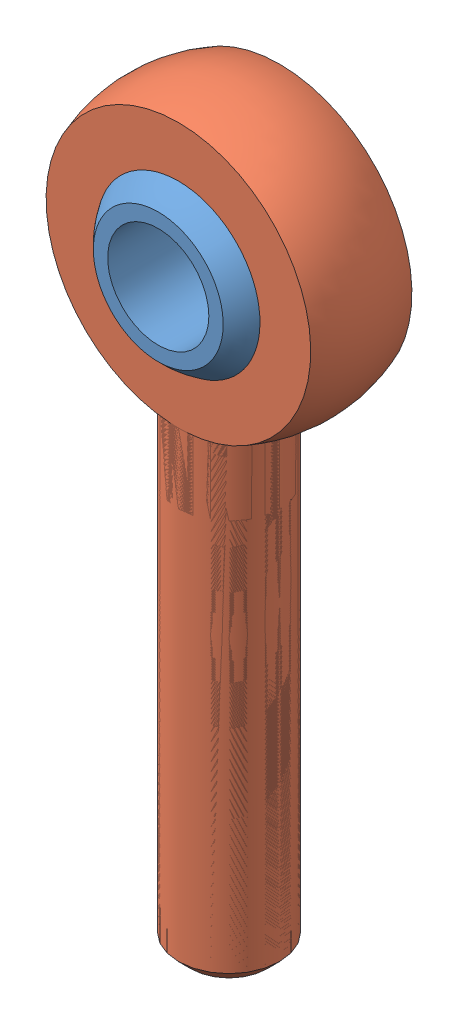
SolidWorks assembly RodEnd312Male, configuration Default. Lengths in mm.
Overall size (22.23 58.75 22.2).
2 component instances, 2 part files, 1 mates.
Components (placement in the parent):
- RodEndBall312-1: RodEndBall312 [Default] at origin size (15.06 15.06 22.2)
- RodEndRace312Male-1: RodEndRace312Male [Default] at origin size (22.23 58.75 7.94)
Mates (geometry in assembly coordinates):
- Concentric1: concentric: sphere of ?; unknown of ?
